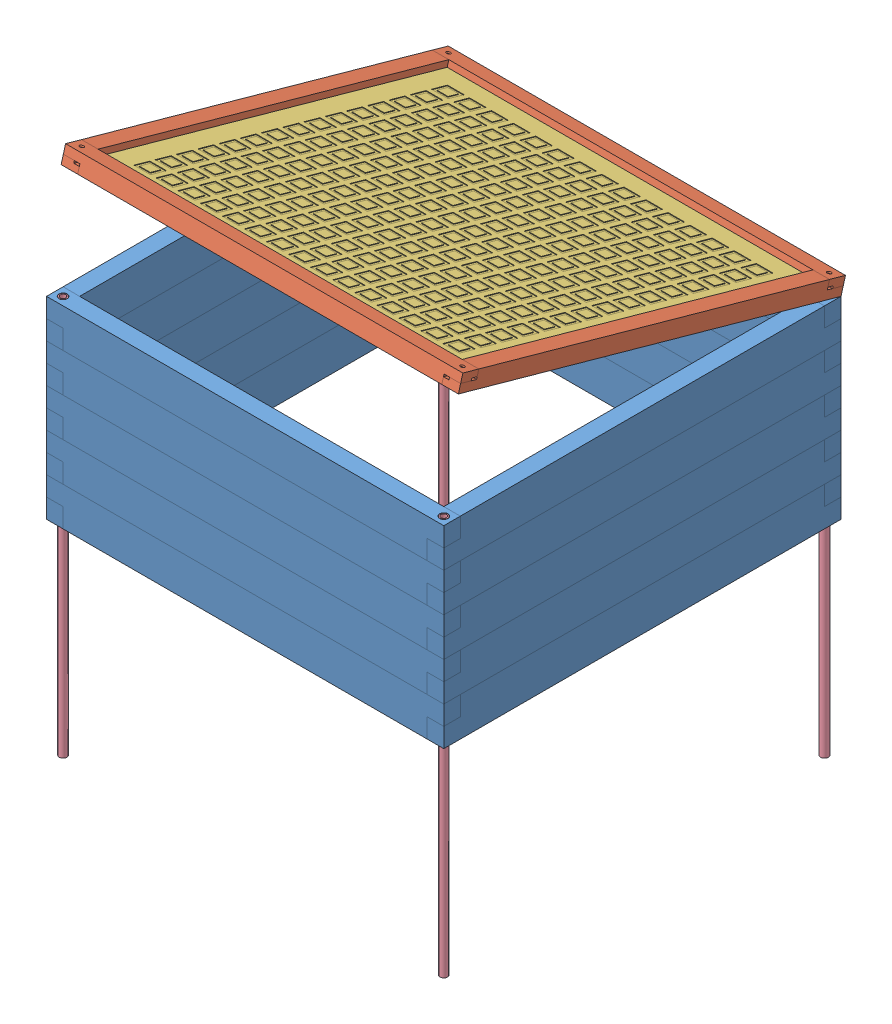
SolidWorks assembly hpgs-001, configuration Default. Lengths in mm.
Overall size (914.4 1196.79 924.64).
30 component instances, 4 part files, 21 mates.
Components (placement in the parent):
- 2x4x36-1: 2x4x36 [Default] at origin size (38.1 88.9 914.4)
- 2x4x36-2: 2x4x36 [Default] at (876.3 0 0) size (38.1 88.9 914.4)
- 2x4x36-3: 2x4x36 [Default] at (914.4 88.9 -914.4) x (0 0 1) z (1 0 0) size (38.1 88.9 914.4)
- 2x4x36-4: 2x4x36 [Default] at (914.4 88.9 -38.1) x (0 0 1) z (1 0 0) size (38.1 88.9 914.4)
- hpgh-002-1: hpgh-002 [Default] at (0 334.5866 -33.6245) x (1 0 0) z (0 0.268686 0.963228) size (914.4 38.1 914.4)
  - 2x2x36-1: 2x2x36 [Default] at origin size (38.1 38.1 914.4)
  - 2x2x36-2: 2x2x36 [Default] at (0 38.1 0) x (0 0 -1) z (-1 0 0) size (38.1 38.1 914.4)
  - 2x2x36-3: 2x2x36 [Default] at (914.4 38.1 -914.4) x (0 0 1) z (1 0 0) size (38.1 38.1 914.4)
  - 2x2x36-4: 2x2x36 [Default] at (914.4 0 -914.4) x (-1 0 0) z (0 0 -1) size (38.1 38.1 914.4)
  - hpgh-top1-1: hpgh-top1 [Default] at (457.2 17.4625 -457.2) size (857.25 6.35 857.25)
- 2x4x36-5: 2x4x36 [Default] at (0 -88.9 0) size (38.1 88.9 914.4)
- 2x4x36-6: 2x4x36 [Default] at (0 -177.8 0) size (38.1 88.9 914.4)
- 2x4x36-7: 2x4x36 [Default] at (0 -266.7 0) size (38.1 88.9 914.4)
- 2x4x36-8: 2x4x36 [Default] at (0 -355.6 0) size (38.1 88.9 914.4)
- 2x4x36-9: 2x4x36 [Default] at (914.4 0 -914.4) x (0 0 1) z (1 0 0) size (38.1 88.9 914.4)
- 2x4x36-10: 2x4x36 [Default] at (914.4 -88.9 -914.4) x (0 0 1) z (1 0 0) size (38.1 88.9 914.4)
- 2x4x36-11: 2x4x36 [Default] at (914.4 -177.8 -914.4) x (0 0 1) z (1 0 0) size (38.1 88.9 914.4)
- 2x4x36-12: 2x4x36 [Default] at (914.4 -266.7 -914.4) x (0 0 1) z (1 0 0) size (38.1 88.9 914.4)
- 2x4x36-13: 2x4x36 [Default] at (876.3 -88.9 0) size (38.1 88.9 914.4)
- 2x4x36-14: 2x4x36 [Default] at (876.3 -177.8 0) size (38.1 88.9 914.4)
- 2x4x36-15: 2x4x36 [Default] at (876.3 -266.7 0) size (38.1 88.9 914.4)
- 2x4x36-16: 2x4x36 [Default] at (876.3 -355.6 0) size (38.1 88.9 914.4)
- 2x4x36-17: 2x4x36 [Default] at (914.4 0 -38.1) x (0 0 1) z (1 0 0) size (38.1 88.9 914.4)
- 2x4x36-18: 2x4x36 [Default] at (914.4 -88.9 -38.1) x (0 0 1) z (1 0 0) size (38.1 88.9 914.4)
- 2x4x36-19: 2x4x36 [Default] at (914.4 -177.8 -38.1) x (0 0 1) z (1 0 0) size (38.1 88.9 914.4)
- 2x4x36-20: 2x4x36 [Default] at (914.4 -266.7 -38.1) x (0 0 1) z (1 0 0) size (38.1 88.9 914.4)
- conduit-1: conduit [Default] at (19.05 -825.5 -895.35) size (17.78 914.4 17.78)
- conduit-2: conduit [Default] at (895.35 -825.5 -19.05) size (17.78 914.4 17.78)
- conduit-3: conduit [Default] at (895.35 -825.5 -895.35) size (17.78 914.4 17.78)
- conduit-4: conduit [Default] at (19.05 -825.5 -19.05) size (17.78 914.4 17.78)
Mates (geometry in assembly coordinates):
- Parallel1: parallel anti-aligned: plane of 2x4x36-1 through (38.1 0 0) normal (1 0 0); plane of 2x4x36-2 through (876.3 0 0) normal (-1 0 0)
- Coincident2: coincident aligned: plane of 2x4x36-1 through (38.1 88.9 0) normal (0 0 1); plane of 2x4x36-2 through (914.4 88.9 0) normal (0 0 1)
- Coincident3: coincident aligned: plane of 2x4x36-2 through (914.4 0 0) normal (1 0 0); plane of 2x4x36-4 through (914.4 0 0) normal (1 0 0)
- Coincident4: coincident aligned: plane of 2x4x36-2 through (914.4 88.9 0) normal (0 1 0); plane of 2x4x36-4 through (914.4 88.9 0) normal (0 1 0)
- Coincident5: coincident aligned: plane of 2x4x36-2 through (914.4 88.9 0) normal (0 0 1); plane of 2x4x36-4 through (914.4 88.9 0) normal (0 0 1)
- Coincident7: coincident aligned: plane of 2x4x36-1 through (0 0 0) normal (-1 0 0); plane of 2x4x36-4 through (0 88.9 0) normal (-1 0 0)
- Coincident8: coincident aligned: plane of 2x4x36-1 through (38.1 88.9 0) normal (0 1 0); plane of 2x4x36-4 through (914.4 88.9 0) normal (0 1 0)
- Coincident9: coincident aligned: plane of 2x4x36-2 through (914.4 0 0) normal (1 0 0); plane of 2x4x36-3 through (914.4 0 -876.3) normal (1 0 0)
- Coincident10: coincident aligned: plane of 2x4x36-2 through (914.4 88.9 0) normal (0 1 0); plane of 2x4x36-3 through (914.4 88.9 -876.3) normal (0 1 0)
- Coincident11: coincident aligned: plane of 2x4x36-2 through (914.4 0 -914.4) normal (0 0 -1); plane of 2x4x36-3 through (914.4 88.9 -914.4) normal (0 0 -1)
- Coincident12: coincident aligned: plane of 2x4x36-2 through (914.4 0 0) normal (1 0 0); plane of hpgh-002-1/2x2x36-4 through (914.4 88.9 -914.4) normal (1 0 0)
- Coincident13: coincident anti-aligned: line of 2x4x36-3 through (914.4 88.9 -914.4) axis (-1 0 0); line of hpgh-002-1/2x2x36-3 through (38.1 88.9 -914.4) axis (1 0 0)
- LimitAngle1: limit planar angle = 0.272029 rad anti-aligned: plane of 2x4x36-2 through (914.4 88.9 0) normal (0 1 0); plane of hpgh-002-1/2x2x36-4 through (876.3 88.9 -914.4) normal (0 -0.963228 0.268686)
- Concentric1: concentric aligned: cylinder of 2x4x36-4 through (19.05 88.9 -19.05) axis (0 -1 0) radius 9.525; cylinder of conduit-4 through (19.05 88.9 -19.05) axis (0 -1 0) radius 8.89
- Coincident15: coincident aligned: plane of 2x4x36-4 through (914.4 88.9 0) normal (0 1 0); plane of conduit-4 through (19.05 88.9 -19.05) normal (0 1 0)
- Concentric2: concentric aligned: cylinder of 2x4x36-3 through (19.05 88.9 -895.35) axis (0 -1 0) radius 9.525; cylinder of conduit-1 through (19.05 88.9 -895.35) axis (0 -1 0) radius 8.89
- Coincident16: coincident aligned: plane of 2x4x36-3 through (914.4 88.9 -876.3) normal (0 1 0); plane of conduit-1 through (19.05 88.9 -895.35) normal (0 1 0)
- Concentric3: concentric aligned: cylinder of 2x4x36-3 through (895.35 88.9 -895.35) axis (0 -1 0) radius 9.525; cylinder of conduit-3 through (895.35 88.9 -895.35) axis (0 -1 0) radius 8.89
- Coincident17: coincident aligned: plane of 2x4x36-3 through (914.4 88.9 -876.3) normal (0 1 0); plane of conduit-3 through (895.35 88.9 -895.35) normal (0 1 0)
- Concentric4: concentric aligned: cylinder of 2x4x36-4 through (895.35 88.9 -19.05) axis (0 -1 0) radius 9.525; cylinder of conduit-2 through (895.35 88.9 -19.05) axis (0 -1 0) radius 8.89
- Coincident18: coincident aligned: plane of 2x4x36-4 through (914.4 88.9 0) normal (0 1 0); plane of conduit-2 through (895.35 88.9 -19.05) normal (0 1 0)
